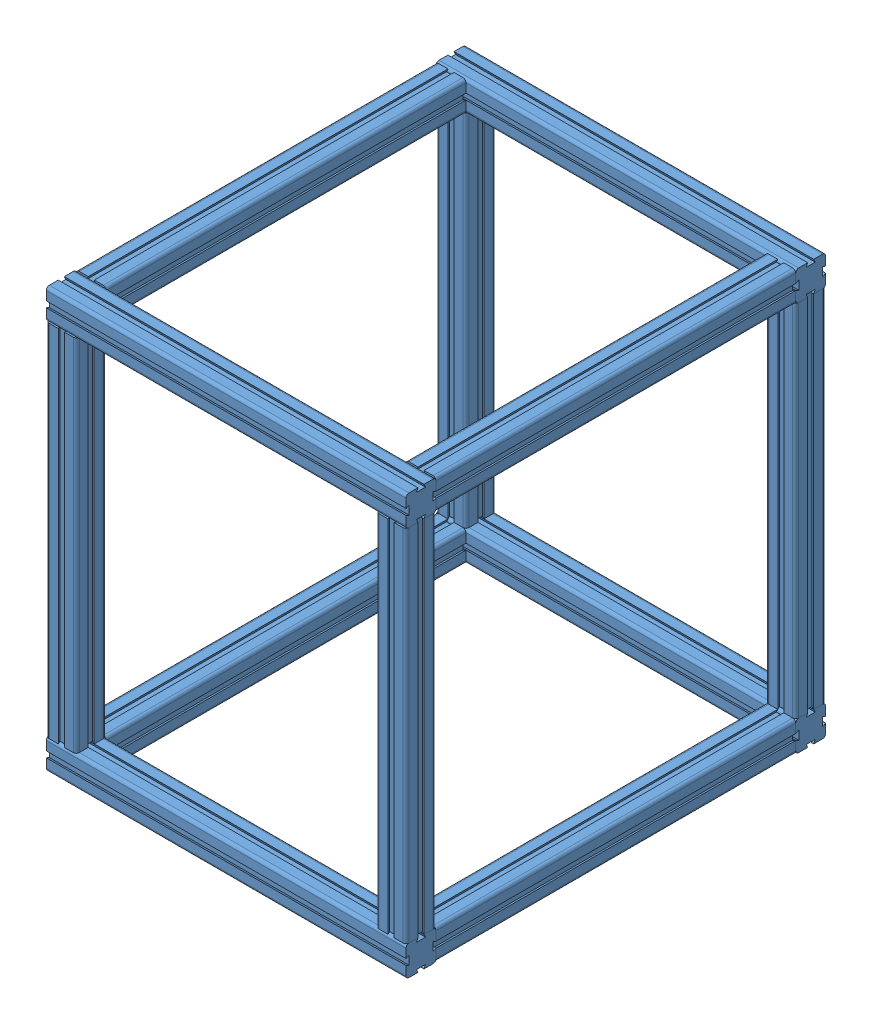
SolidWorks assembly Assem1, configuration Default. Lengths in mm.
Overall size (600 700 700).
12 component instances, 1 part files, 22 mates.
Components (placement in the parent):
- fabricagetechnieken kist-1: fabricagetechnieken kist [Default] at (-29.3108 -16.3751 296.4151) size (50 50 600)
- fabricagetechnieken kist-2: fabricagetechnieken kist [Default] at (520.6892 -16.3751 296.4151) size (50 50 600)
- fabricagetechnieken kist-3: fabricagetechnieken kist [Default] at (570.6892 -16.3751 346.4151) x (0 0 -1) z (1 0 0) size (50 50 600)
- fabricagetechnieken kist-4: fabricagetechnieken kist [Default] at (-29.3108 -16.3751 -353.5849) x (0 0 1) z (-1 0 0) size (50 50 600)
- fabricagetechnieken kist-5: fabricagetechnieken kist [Default] at (-29.3108 633.6249 -353.5849) x (0 0 1) z (-1 0 0) size (50 50 600)
- fabricagetechnieken kist-6: fabricagetechnieken kist [Default] at (570.6892 633.6249 346.4151) x (0 0 -1) z (1 0 0) size (50 50 600)
- fabricagetechnieken kist-7: fabricagetechnieken kist [Default] at (520.6892 633.6249 296.4151) size (50 50 600)
- fabricagetechnieken kist-8: fabricagetechnieken kist [Default] at (-29.3108 633.6249 296.4151) size (50 50 600)
- fabricagetechnieken kist-9: fabricagetechnieken kist [Default] at (-29.3108 33.6249 296.4151) x (1 0 0) z (0 -1 0) size (50 50 600)
- fabricagetechnieken kist-10: fabricagetechnieken kist [Default] at (-29.3108 33.6249 -353.5849) x (1 0 0) z (0 -1 0) size (50 50 600)
- fabricagetechnieken kist-11: fabricagetechnieken kist [Default] at (520.6892 33.6249 -353.5849) x (1 0 0) z (0 -1 0) size (50 50 600)
- fabricagetechnieken kist-12: fabricagetechnieken kist [Default] at (520.6892 33.6249 296.4151) x (1 0 0) z (0 -1 0) size (50 50 600)
Mates (geometry in assembly coordinates):
- Coincident1: coincident: plane of fabricagetechnieken kist-1 through (-24.3108 28.6249 296.4151) normal (0 0 1); plane of fabricagetechnieken kist-3 through (-29.3108 28.6249 296.4151) normal (0 0 -1)
- Coincident2: coincident: line of fabricagetechnieken kist-1 through (-29.3108 3.6249 296.4151) axis (0 -1 0); line of fabricagetechnieken kist-3 through (-29.3108 -11.3751 296.4151) axis (0 1 0)
- Coincident6: coincident: line of fabricagetechnieken kist-1 through (-29.3108 3.6249 -303.5849) axis (0 0 1); point of fabricagetechnieken kist-3
- Coincident7: coincident: plane of fabricagetechnieken kist-2 through (525.6892 28.6249 296.4151) normal (0 0 1); plane of fabricagetechnieken kist-3 through (-29.3108 28.6249 296.4151) normal (0 0 -1)
- Coincident8: coincident: line of fabricagetechnieken kist-2 through (570.6892 13.6249 296.4151) axis (0 1 0); line of fabricagetechnieken kist-3 through (570.6892 13.6249 296.4151) axis (0 1 0)
- Coincident9: coincident: point of fabricagetechnieken kist-2; point of fabricagetechnieken kist-3
- Coincident10: coincident: plane of fabricagetechnieken kist-1 through (-24.3108 28.6249 -303.5849) normal (0 0 -1); plane of fabricagetechnieken kist-4 through (570.6892 28.6249 -303.5849) normal (0 0 1)
- Coincident11: coincident: point of fabricagetechnieken kist-2; point of fabricagetechnieken kist-4
- Coincident12: coincident: plane of fabricagetechnieken kist-6 through (-29.3108 678.6249 296.4151) normal (0 0 -1); plane of fabricagetechnieken kist-7 through (525.6892 678.6249 296.4151) normal (0 0 1)
- Coincident13: coincident: point of fabricagetechnieken kist-6; line of fabricagetechnieken kist-8 through (-29.3108 653.6249 -303.5849) axis (0 0 1)
- Coincident14: coincident: plane of fabricagetechnieken kist-5 through (570.6892 678.6249 -303.5849) normal (0 0 1); plane of fabricagetechnieken kist-8 through (-24.3108 678.6249 -303.5849) normal (0 0 -1)
- Coincident15: coincident: line of fabricagetechnieken kist-6 through (-29.3108 638.6249 296.4151) axis (0 1 0); line of fabricagetechnieken kist-8 through (-29.3108 653.6249 296.4151) axis (0 -1 0)
- Coincident16: coincident: plane of fabricagetechnieken kist-6 through (-29.3108 678.6249 296.4151) normal (0 0 -1); plane of fabricagetechnieken kist-8 through (-24.3108 678.6249 296.4151) normal (0 0 1)
- Coincident17: coincident: line of fabricagetechnieken kist-6 through (570.6892 663.6249 296.4151) axis (0 1 0); line of fabricagetechnieken kist-7 through (570.6892 663.6249 296.4151) axis (0 1 0)
- Coincident18: coincident: point of fabricagetechnieken kist-6; point of fabricagetechnieken kist-7
- Coincident19: coincident: point of fabricagetechnieken kist-5; point of fabricagetechnieken kist-7
- Coincident20: coincident: plane of fabricagetechnieken kist-3 through (-29.3108 33.6249 341.4151) normal (0 1 0); plane of fabricagetechnieken kist-9 through (-24.3108 33.6249 341.4151) normal (0 -1 0)
- Coincident21: coincident: point of fabricagetechnieken kist-3; point of fabricagetechnieken kist-9
- Coincident22: coincident: point of fabricagetechnieken kist-6; point of fabricagetechnieken kist-9
- Coincident23: coincident: point of fabricagetechnieken kist-4; point of fabricagetechnieken kist-10
- Coincident24: coincident: point of fabricagetechnieken kist-4; point of fabricagetechnieken kist-11
- Coincident25: coincident: point of fabricagetechnieken kist-3; point of fabricagetechnieken kist-12
